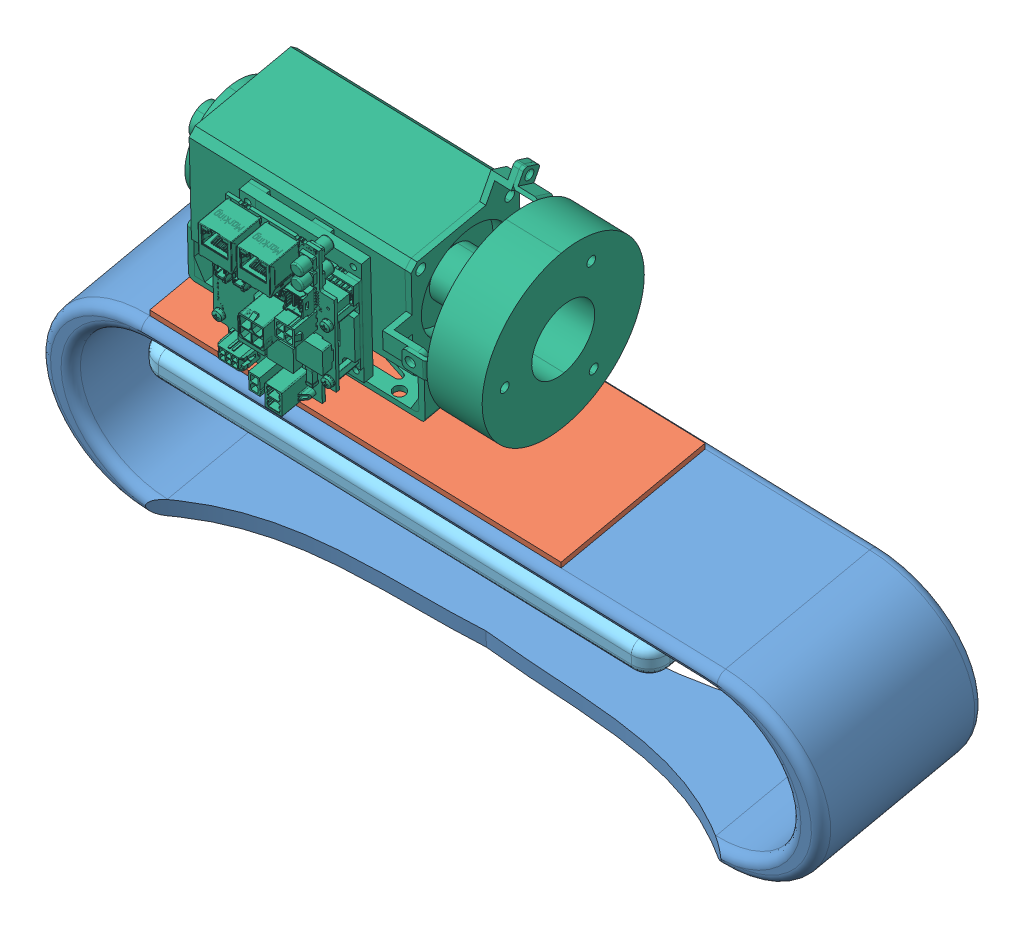
SolidWorks assembly Assem1, configuration Default. Lengths in mm.
Overall size (393.53 248.47 156.24).
6 component instances, 6 part files, 18 mates.
Components (placement in the parent):
- 2. Belt-1: 2. Belt [Default] at (-326.2667 516.8322 302.678) x (0.991795 -0.105539 -0.072143) z (0.056471 -0.1446 0.987877) size (380 100 91.64)
- 3. carbon fiber plate-1: 3. carbon fiber plate [Default] at (-223.8938 561.9777 257.8819) x (-0.991795 0.105539 0.072143) z (0.114691 0.983846 0.137454) size (200 80 3)
- 4. carbon attachement_1-1: 4. carbon attachement_1 [Default] at (-141.9598 541.7998 250.2447) x (0.991795 -0.105539 -0.072143) z (0.114691 0.983846 0.137454) size (10 80 3)
- 5. carbon attachement_2-1: 5. carbon attachement_2 [Default] at (-312.8807 559.9878 262.6775) x (0.991795 -0.105539 -0.072143) z (0.114691 0.983846 0.137454) size (10 80 3)
- 6. Vibration absorbing material-1: 6. Vibration absorbing material [Default] at (-204.0932 533.4786 252.5216) x (0.991795 -0.105539 -0.072143) z (0.114691 0.983846 0.137454) size (250 90 15)
- 9. motor_controller-1: 9. motor_controller [Default] at (-142.5711 538.5584 226.1337) x (-0.114691 -0.983846 -0.137454) z (-0.991795 0.105539 0.072143) size (99.44 114.56 175.11)
Mates (geometry in assembly coordinates):
- Coincident1: coincident: plane of 2. Belt-1 through (-325.6145 579.0385 220.6417) normal (0.114691 0.983846 0.137454); plane of 3. carbon fiber plate-1 through (-223.8938 561.9777 257.8819) normal (-0.114691 -0.983846 -0.137454)
- Coincident2: coincident: line of 2. Belt-1 through (-320.8145 566.7475 304.6113) axis (0.991795 -0.105539 -0.072143); plane of 3. carbon fiber plate-1 through (-122.1114 548.5913 290.5951) normal (0.056471 -0.1446 0.987877)
- Coincident3: coincident: line of 2. Belt-1 through (-325.3321 578.3155 225.5811) axis (0.056471 -0.1446 0.987877); plane of 3. carbon fiber plate-1 through (-320.4704 569.6991 305.0237) normal (-0.991795 0.105539 0.072143)
- Coincident7: coincident: plane of 2. Belt-1 through (-320.0368 569.974 218.9961) normal (-0.114691 -0.983846 -0.137454); plane of 5. carbon attachement_2-1 through (-312.5366 562.9393 263.0898) normal (0.114691 0.983846 0.137454)
- Coincident8: coincident: line of 2. Belt-1 through (-319.7544 569.251 223.9354) axis (0.991795 -0.105539 -0.072143); line of 5. carbon attachement_2-1 through (-309.8365 568.1957 223.214) axis (-0.991795 0.105539 0.072143)
- Coincident9: coincident: line of 2. Belt-1 through (-319.7544 569.251 223.9354) axis (0.056471 -0.1446 0.987877); plane of 5. carbon attachement_2-1 through (-319.7544 569.251 223.9354) normal (-0.991795 0.105539 0.072143)
- Coincident10: coincident: plane of 2. Belt-1 through (-320.0368 569.974 218.9961) normal (-0.114691 -0.983846 -0.137454); plane of 4. carbon attachement_1-1 through (-141.6157 544.7513 250.6571) normal (0.114691 0.983846 0.137454)
- Coincident11: coincident: line of 2. Belt-1 through (-50.6404 529.5269 283.719) axis (-0.991795 0.105539 0.072143); plane of 4. carbon attachement_1-1 through (-144.3159 539.495 290.5329) normal (0.056471 -0.1446 0.987877)
- Coincident12: coincident: line of 2. Belt-1 through (-319.7544 569.251 223.9354) axis (0.991795 -0.105539 -0.072143); plane of 4. carbon attachement_1-1 through (-148.8335 551.063 211.5027) normal (-0.056471 0.1446 -0.987877)
- Coincident15: coincident: plane of 5. carbon attachement_2-1 through (-312.8807 559.9878 262.6775) normal (-0.114691 -0.983846 -0.137454); plane of 6. Vibration absorbing material-1 through (-202.3728 548.2363 254.5834) normal (0.114691 0.983846 0.137454)
- Coincident16: coincident: line of 2. Belt-1 through (-314.4699 561.1517 308.434) axis (0.991795 -0.105539 -0.072143); plane of 6. Vibration absorbing material-1 through (-323.806 554.9216 308.0557) normal (0.056471 -0.1446 0.987877)
- Coincident17: coincident: plane of 4. carbon attachement_1-1 through (-141.9598 541.7998 250.2447) normal (-0.114691 -0.983846 -0.137454); plane of 6. Vibration absorbing material-1 through (-202.3728 548.2363 254.5834) normal (0.114691 0.983846 0.137454)
- Lock1: lock: unknown of 2. Belt-1; unknown of 3. carbon fiber plate-1
- Lock2: lock: unknown of 2. Belt-1; unknown of 4. carbon attachement_1-1
- Lock3: lock: unknown of 4. carbon attachement_1-1; unknown of 6. Vibration absorbing material-1
- Tangent1: tangent: plane of 3. carbon fiber plate-1 through (-223.5498 564.9292 258.2943) normal (0.114691 0.983846 0.137454); face of 9. motor_controller-1
- Tangent2: tangent: plane of 3. carbon fiber plate-1 through (-320.4704 569.6991 305.0237) normal (-0.991795 0.105539 0.072143); face of 9. motor_controller-1
- Lock4: lock: unknown of 3. carbon fiber plate-1; unknown of 9. motor_controller-1
